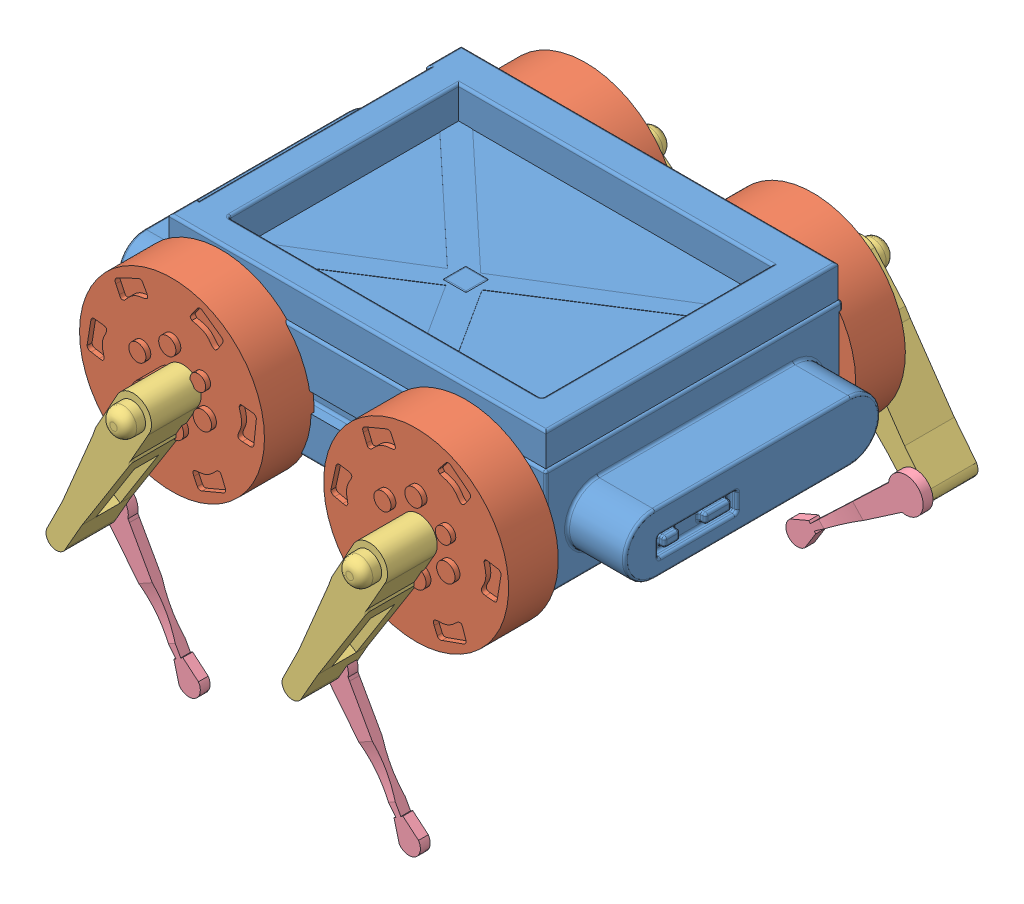
SolidWorks assembly Assem1, configuration Default. Lengths in mm.
Overall size (1776.78 1556.04 554.04).
14 component instances, 4 part files, 11 mates.
Components (placement in the parent):
- Assembly 1-1: Assembly 1 [Default] at (1345.2762 945.3559 2551.4585) size (509 143.56 303.6)
  - main body-1: main body [Default] at (483.0032 525.0975 601.7796) size (509 143.56 303.6)
- circular joint biggest-3: circular joint biggest [Default] at (1768.4037 1444.3566 3359.8289) x (0.998207 -0.059851 0) z (0 0 1) size (1224 1224 154.76)
- circular joint biggest-4: circular joint biggest [Default] at (1510.8281 1445.1741 3351.5847) x (0.999992 -0.004002 0) z (0 0 1) size (1224 1224 154.76)
- circular joint biggest-5: circular joint biggest [Default] at (1748.5942 1435.9684 2953.2085) x (-0.296757 -0.954953 0) z (0 0 -1) size (1224 1224 154.76)
- circular joint biggest-6: circular joint biggest [Default] at (1502.9967 1443.3518 2952.8732) x (-0.94542 -0.325854 0) z (0 0 -1) size (1224 1224 154.76)
- leg upper link-2: leg upper link [Default] at (1712.1633 1290.1963 2947.4359) x (-0.978681 -0.205386 0) z (0 0 -1) size (107.89 178.6 69.8)
- leg lower link-2: leg lower link [Default] at (1668.1969 1399.1482 2958.5268) x (-0.955838 0.293894 0) z (0 0 -1) size (133.61 169.45 38.12)
- leg upper link-3: leg upper link [Default] at (1521.1697 1276.3646 2952.8732) x (-0.923728 -0.383049 0) z (0 0 -1) size (107.89 178.6 69.8)
- leg lower link-3: leg lower link [Default] at (1466.6152 1278.2898 2963.9142) x (-0.923728 -0.383049 0) z (0 0 -1) size (133.61 169.45 38.12)
- leg upper link-5: leg upper link [Default] at (1823.4881 1292.2311 3361.8745) size (107.89 178.6 69.8)
- leg lower link-4: leg lower link [Default] at (1873.1442 1314.9066 3364.0965) size (133.61 169.45 38.12)
- leg upper link-6: leg upper link [Default] at (1571.8865 1293.4937 3351.5847) size (107.89 178.6 69.8)
- leg lower link-5: leg lower link [Default] at (1621.5426 1316.1691 3337.4537) size (133.61 169.45 38.12)
Mates (geometry in assembly coordinates):
- Coincident6: coincident: cylinder of Assembly 1-1/main body-1 through (1753.9895 1452.2856 3225.8597) axis (0 0 1) radius 30.4308; circle of circular joint biggest-3
- Coincident7: coincident: cylinder of Assembly 1-1/main body-1 through (1495.9935 1452.2856 3225.8597) axis (0 0 1) radius 30.4308; circle of circular joint biggest-4
- Coincident9: coincident: circle of Assembly 1-1/main body-1; cylinder of circular joint biggest-5 through (1746.2705 1452.2544 3081.9705) axis (0 0 -1) radius 30.4308
- Coincident10: coincident: circle of Assembly 1-1/main body-1; cylinder of circular joint biggest-6 through (1514.7504 1454.862 3081.6352) axis (0 0 -1) radius 30.4308
- Concentric4: concentric: cylinder of circular joint biggest-5 through (1750.6572 1452.9927 2927.2085) axis (0 0 1) radius 15.65; circle of leg upper link-2
- Coincident11: coincident: circle of leg upper link-2; cylinder of leg lower link-2 through (1851.3918 1332.6746 2922.5268) axis (0 0 1) radius 9.3327
- Coincident12: coincident: circle of circular joint biggest-6; plane of leg upper link-3 through (1528.8542 1443.4736 2926.8732) normal (0 0 1)
- Coincident13: coincident: circle of leg upper link-3; cylinder of leg lower link-3 through (1650.1253 1343.8883 2927.9142) axis (0 0 1) radius 9.3327
- Coincident14: coincident: cylinder of leg upper link-5 through (1678.5033 1305.2084 3387.8745) axis (0 0 -1) radius 9.3327; circle of leg lower link-4
- Coincident15: coincident: circle of circular joint biggest-4; plane of leg upper link-6 through (1500.7772 1444.9134 3377.5847) normal (0 0 -1)
- Coincident16: coincident: cylinder of leg upper link-6 through (1426.9018 1306.4709 3377.5847) axis (0 0 -1) radius 9.3327; circle of leg lower link-5
